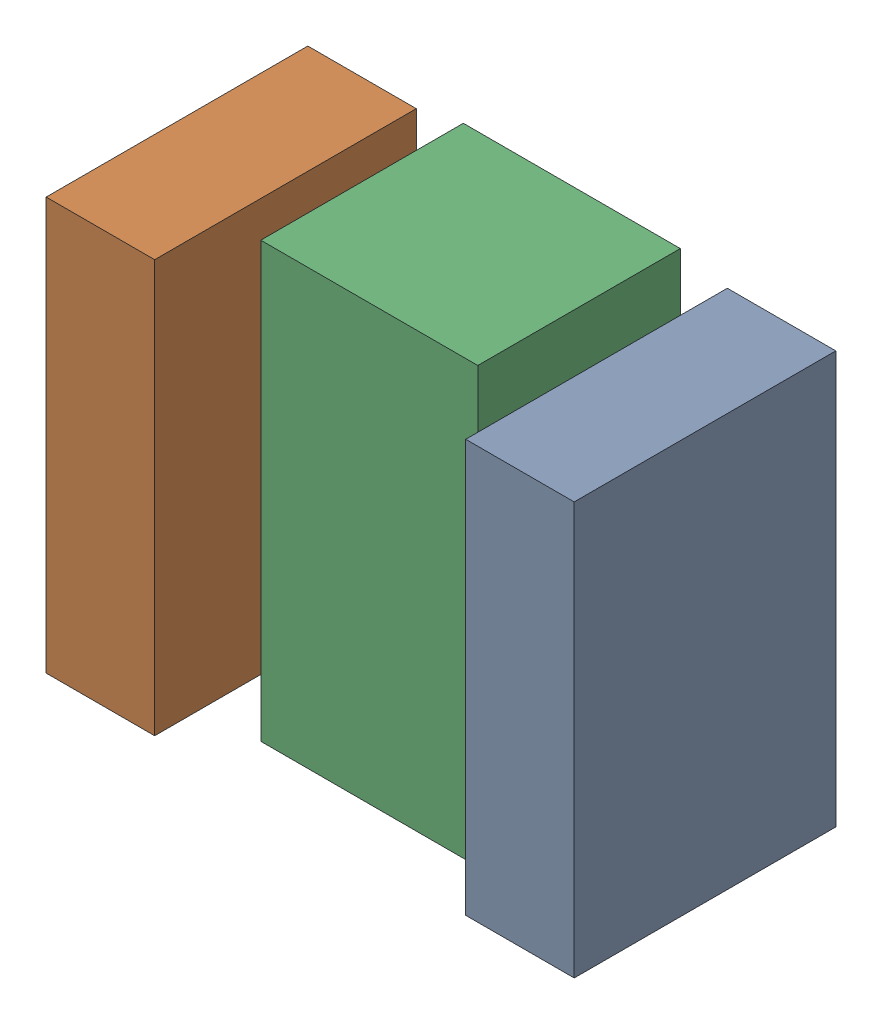
SolidWorks assembly C11_Motor_10Kanaloa_v2.0.0_Motor, configuration Default. Lengths in mm.
Overall size (3.65 3 1.81).
6 component instances, 2 part files, 0 mates.
Components (placement in the parent):
- 334788400-1: 334788400 [Default] at (78.936 163.83 0) size (0.75 2.85 1.81)
  - Extruded_5-1: Extruded_5 [Default] at origin size (0.75 2.85 1.81)
- 334788400-2: 334788400 [Default] at (76.036 163.83 0) size (0.75 2.85 1.81)
  - Extruded_5-1: Extruded_5 [Default] at origin size (0.75 2.85 1.81)
- 334788656-1: 334788656 [Default] at (77.486 163.83 0) size (1.5 3 1.4)
  - Extruded_1-1: Extruded_1 [Default] at origin size (1.5 3 1.4)
